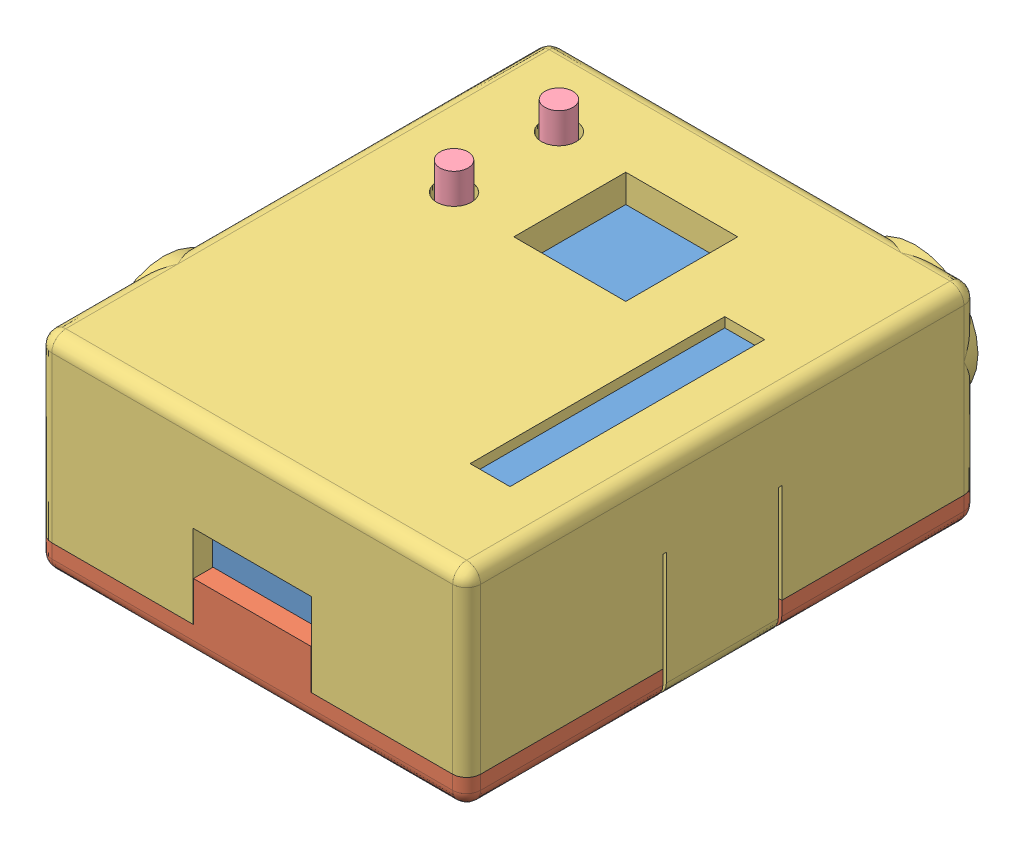
SolidWorks assembly lepton case, configuration Default. Lengths in mm.
Overall size (31.09 16.75 37.02).
5 component instances, 4 part files, 13 mates.
Components (placement in the parent):
- Board-1: Board [Default] at origin size (22.45 12.1 32.25)
- Bottom-1: Bottom [Default] at origin size (30.65 8.6 36.55)
- top-1: top [with  head] at origin size (31.09 14.75 37.02)
- button-1: button [Default] at (-8.9 1.45 -12.55) x (0 1 0) z (-0.199622 0 0.979873) size (11 3 3)
- button-2: button [Default] at (-8.9 1.45 -5.05) x (0 1 0) z (-0.91198 0 0.410236) size (11 3 3)
Mates (geometry in assembly coordinates):
- Coincident1: coincident aligned: plane of Board-1 through (0 0 0) normal (0 0 1)
- Coincident2: coincident aligned: plane of Board-1 through (0 0 0) normal (0 1 0)
- Coincident3: coincident aligned: plane of Board-1 through (0 0 0) normal (1 0 0)
- Coincident4: coincident aligned: plane of Bottom-1 through (0 0 0) normal (0 0 1)
- Coincident6: coincident aligned: plane of Bottom-1 through (0 0 0) normal (0 1 0)
- Coincident7: coincident aligned: plane of Bottom-1 through (0 0 0) normal (1 0 0)
- Coincident8: coincident aligned: plane of top-1 through (0 0 0) normal (0 0 1)
- Coincident9: coincident aligned: plane of top-1 through (0 0 0) normal (0 1 0)
- Coincident10: coincident aligned: plane of top-1 through (0 0 0) normal (1 0 0)
- Concentric1: concentric aligned: cylinder of top-1 through (-8.9 18.45 -5.05) axis (0 -1 0) radius 1.25; cylinder of button-2 through (-8.9 1.45 -5.05) axis (0 -1 0) radius 1
- Concentric2: concentric aligned: cylinder of top-1 through (-8.9 18.45 -12.55) axis (0 -1 0) radius 1.25; cylinder of button-1 through (-8.9 1.45 -12.55) axis (0 -1 0) radius 1
- Coincident11: coincident anti-aligned: plane of top-1 through (0 8.45 0) normal (0 -1 0); plane of button-1 through (-10.3698 8.45 -12.8494) normal (0 1 0)
- Coincident12: coincident anti-aligned: plane of top-1 through (0 8.45 0) normal (0 -1 0); plane of button-2 through (-9.5154 8.45 -6.418) normal (0 1 0)
